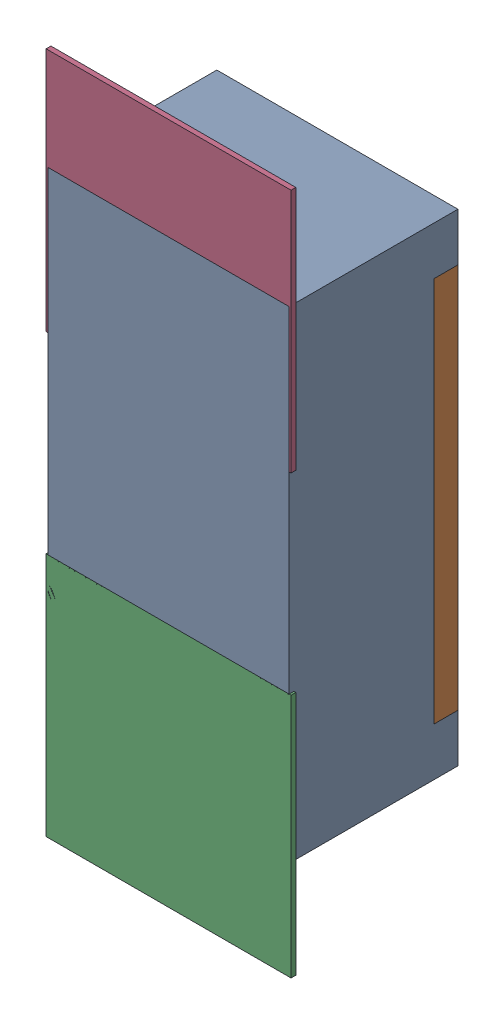
SolidWorks assembly R102, configuration Défaut. Lengths in mm.
Overall size (0.51 1.42 0.35).
5 component instances, 2 part files, 0 mates.
Components (placement in the parent):
- R0402-1: R0402 [Défaut] at (19.6343 -21.648 -2.0818) x (0 -1 0) z (0 0 -1) size (1 0.5 0.35)
- 6504207776-1: 6504207776 [Défaut] at (19.6342 -22.098 -2.0918) size (0.51 0.51 0.01)
  - Extruded-1: Extruded [Défaut] at origin size (0.51 0.51 0.01)
- 6504207776-2: 6504207776 [Défaut] at (19.6342 -21.1909 -2.0918) size (0.51 0.51 0.01)
  - Extruded-1: Extruded [Défaut] at origin size (0.51 0.51 0.01)
